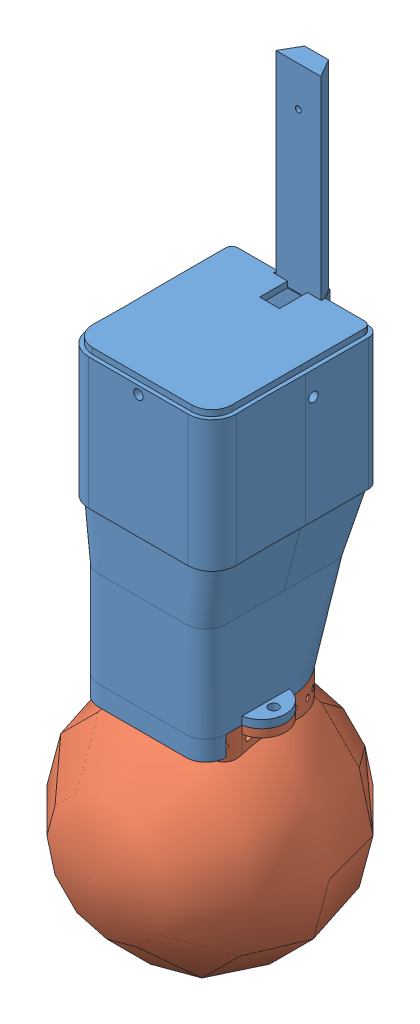
SolidWorks assembly Assem1, configuration Default. Lengths in mm.
Overall size (40.64 68.04 35.81).
3 component instances, 2 part files, 6 mates.
Components (placement in the parent):
- npx_cap_tall_longrear-1: npx_cap_tall_longrear [Default] at (17.6624 9.3568 38.0979) x (-1 0 0) z (0 0 1) size (40.64 68.04 35.8)
- npx_cap_base-1: npx_cap_base [Default] at (17.6624 9.3568 38.0979) size (30 30.25 30)
- npx_cap_tall_longrear-2: npx_cap_tall_longrear [lid] at (17.6624 63.8568 38.1079) size (21 23.5 28.5)
Mates (geometry in assembly coordinates):
- Coincident1: coincident: plane of npx_cap_tall_longrear-1 through (17.6624 9.3568 38.0979) normal (-1 0 0); plane of npx_cap_base-1 through (17.6624 9.3568 38.0979) normal (1 0 0)
- Concentric1: concentric: cylinder of npx_cap_tall_longrear-1 through (17.6624 9.3568 28.3479) axis (0 -1 0) radius 0.6; circle of npx_cap_base-1
- Coincident2: coincident anti-aligned: plane of npx_cap_tall_longrear-1 through (17.1624 9.3568 37.5979) normal (0 -1 0); plane of npx_cap_base-1 through (18.1624 9.3568 37.5979) normal (0 1 0)
- Coincident3: coincident: plane of npx_cap_tall_longrear-1 through (17.6624 9.3568 38.0979) normal (-1 0 0); plane of npx_cap_tall_longrear-2 through (17.6624 72.3181 38.1079) normal (1 0 0)
- Coincident4: coincident: plane of npx_cap_tall_longrear-1 through (11.412 44.8568 47.5979) normal (0 0 -1); plane of npx_cap_tall_longrear-2 through (17.6624 48.8181 47.5979) normal (0 0 1)
- Coincident5: coincident anti-aligned: plane of npx_cap_tall_longrear-1 through (23.9127 44.8568 45.5979) normal (0 1 0); plane of npx_cap_tall_longrear-2 through (17.6624 44.8568 38.1079) normal (0 -1 0)
